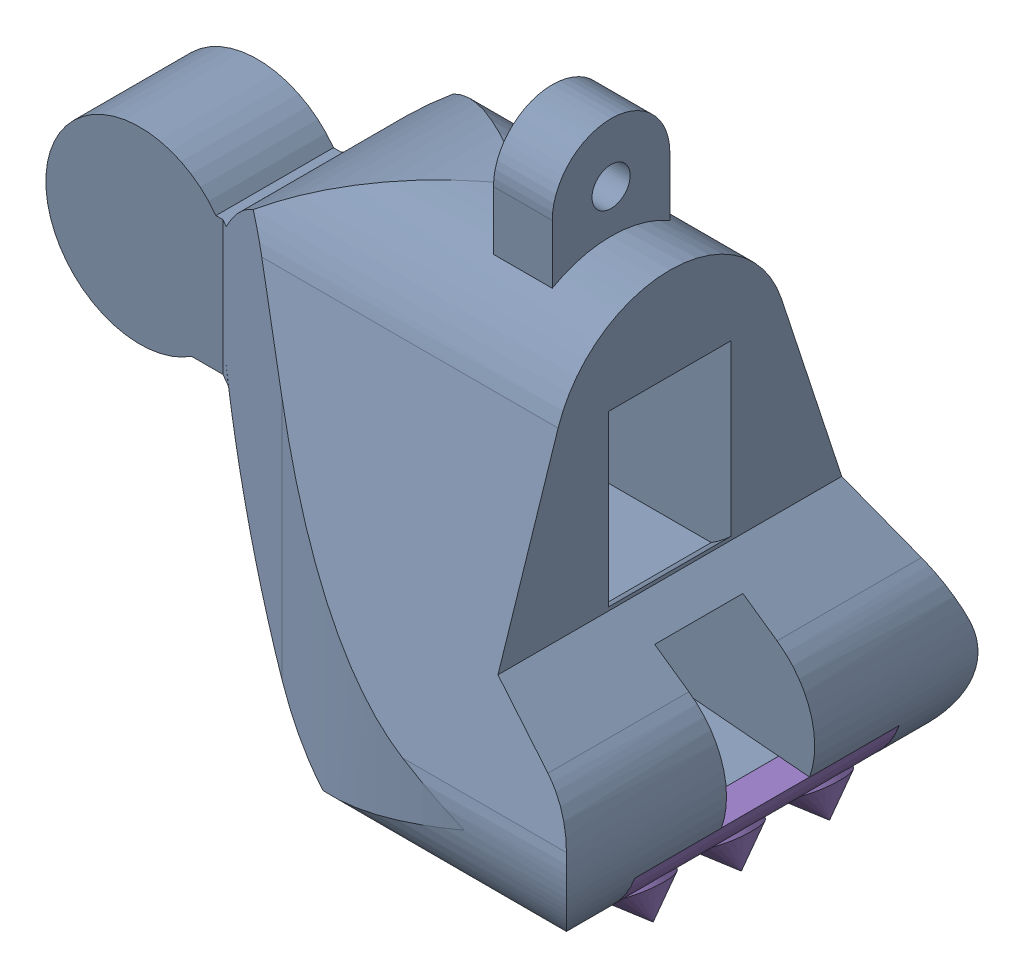
SolidWorks assembly A-Tars-001, configuration Default. Lengths in mm.
Overall size (36.05 32.49 22.22).
2 component instances, 2 part files, 3 mates.
Components (placement in the parent):
- M-Tars-003-1: M-Tars-003 [Default] at (-33.6357 -2.5931 9.7938) size (36.05 30.9 22.23)
- M-Tars-004-1: M-Tars-004 [Default] at (-9.1684 -18.4681 20.1126) x (-1 0 0) z (0 0 -1) size (17.21 4.9 14.29)
Mates (geometry in assembly coordinates):
- Coincident1: coincident anti-aligned: plane of Foot Segment Hybrid-1 through (-7.4278 -16.8806 20.1126) normal (0 -1 0); plane of Foot Pad-1 through (-7.4336 -16.8806 5.8251) normal (0 1 0)
- Coincident2: coincident anti-aligned: plane of Foot Segment Hybrid-1 through (-7.4278 -13.7056 20.1126) normal (0 0 -1); plane of Foot Pad-1 through (-10.9033 0.5819 20.1126) normal (0 0 1)
- Coincident3: coincident anti-aligned: plane of Foot Segment Hybrid-1 through (-20.1517 -16.0696 20.1126) normal (0.258819 -0.965926 0); plane of Foot Pad-1 through (-20.1552 -16.0705 5.8251) normal (-0.258819 0.965926 0)
